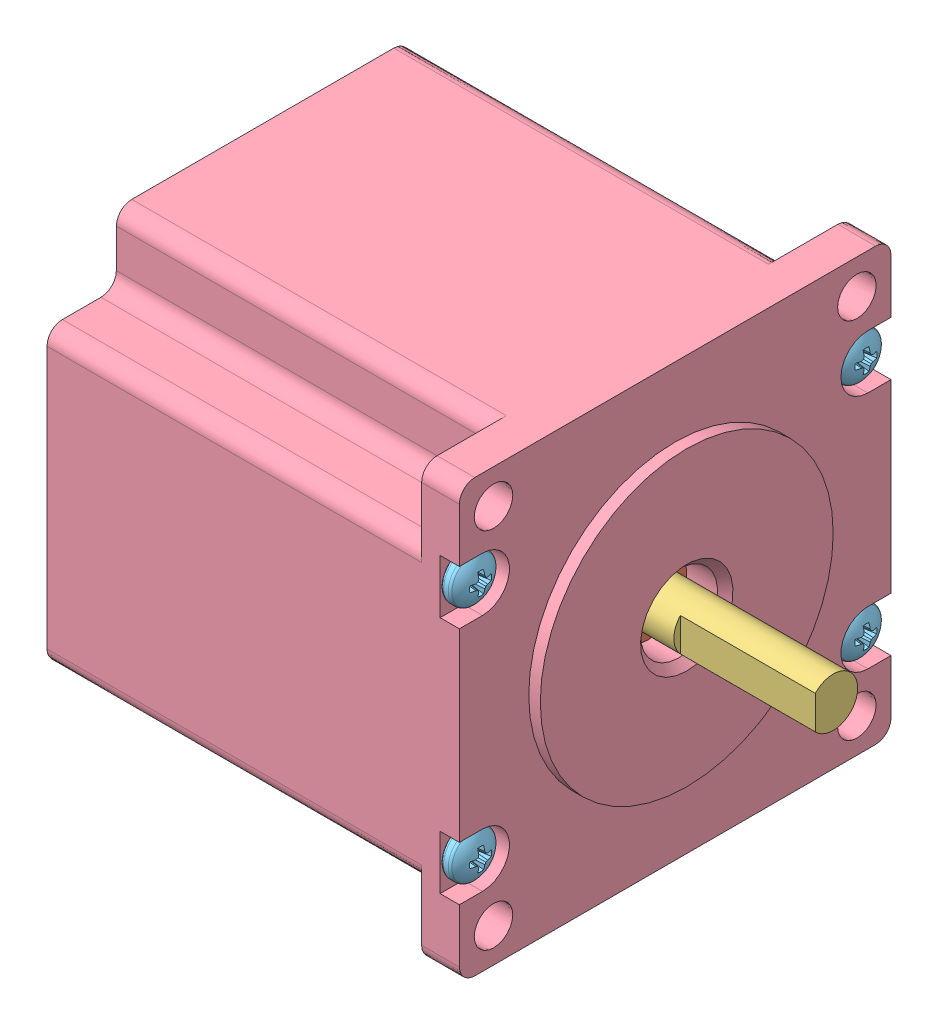
SolidWorks assembly nema23Assy, configuration Default. Lengths in mm.
Overall size (74 56 56).
10 component instances, 6 part files, 0 mates.
Components (placement in the parent):
- nema23.stp-1: nema23.stp [Default] at origin size (74 56 56)
  - BACK_BEARING.stp-1: BACK_BEARING.stp [Default] at origin size (5 20 20)
  - FRONT_BEARING.stp-1: FRONT_BEARING.stp [Default] at origin size (5 20 20)
  - SHAFT.stp-1: SHAFT.stp [Default] at origin size (74 6.35 6.35)
  - NEMA23_1.stp-1: NEMA23_1.stp [Default] at origin size (55 56 56)
  - M3X6.stp-1: M3X6.stp [Default] at (-8.5 -15.5 -25) x (0 0 1) z (1 0 0) size (6 6 8.44)
  - M3X6.stp-2: M3X6.stp [Default] at (-8.5 15.5 25) x (0 0 1) z (1 0 0) size (6 6 8.44)
  - M3X6.stp-3: M3X6.stp [Default] at (-8.5 15.5 -25) x (0 0 1) z (1 0 0) size (6 6 8.44)
  - M3X6.stp-4: M3X6.stp [Default] at (-8.5 -15.5 25) x (0 0 1) z (1 0 0) size (6 6 8.44)
  - TESTPLATE.stp-1: TESTPLATE.stp [Default] at origin (suppressed, hidden)
